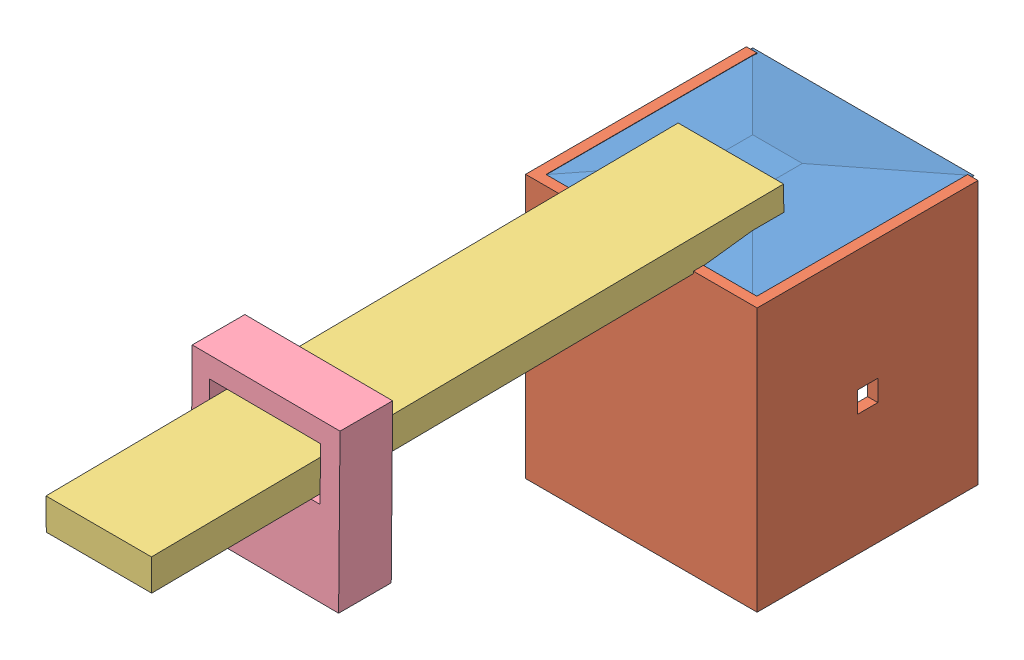
SolidWorks assembly Ensamblaje1, configuration Predeterminado. Lengths in mm.
Overall size (55.8 78.25 184.73).
6 component instances, 4 part files, 0 mates.
Components (placement in the parent):
- canasta_cuadrada-1: canasta_cuadrada [Predeterminado] at (-0.9546 -28.2208 65.73) size (55.8 65.73 54.07)
  - base_canasta2-1: base_canasta2 [Predeterminado] at (13.4907 -5.1974 50.695) size (53.34 2.54 53.34)
  - pared_cansta2-1: pared_cansta2 [Predeterminado] at (27.215 -5.2833 27.493) size (55.8 63.5 53.22)
  - base_canasta2-2: base_canasta2 [Predeterminado] at (13.2939 57.9067 50.673) size (53.34 2.54 53.34)
- palanca-1: palanca [Predeterminado] at (33.4289 36.4746 202.9283) x (0.000451 -0.010457 0.999945) z (-0.001422 -0.999944 -0.010456) size (152.4 25.4 7.62)
- pivote-1: pivote [Predeterminado] at (-18.6388 6.7139 268.1747) x (0.001492 0.001913 0.999997) z (0.007041 0.999973 -0.001924) size (12.7 35.56 38.1)
